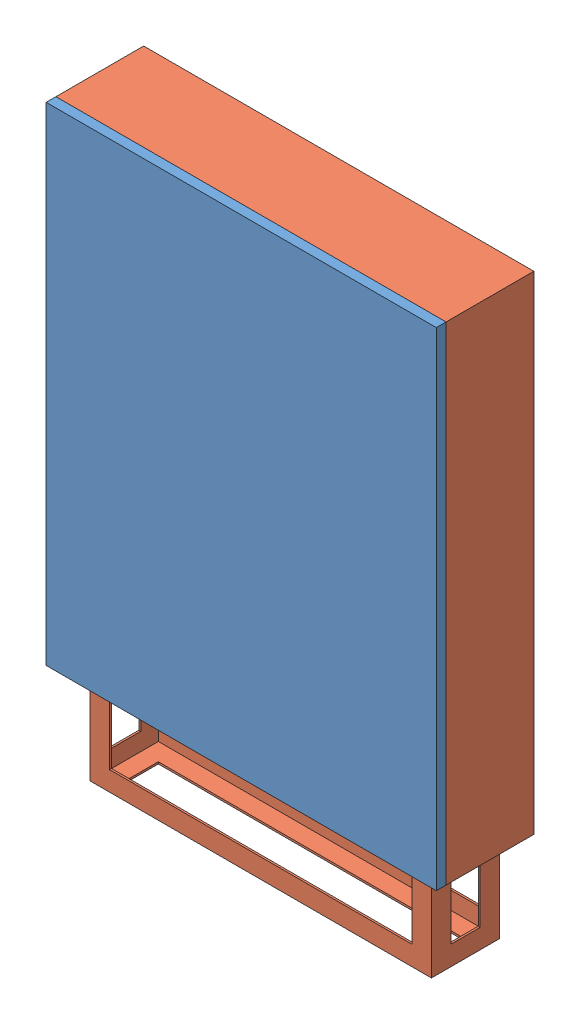
SolidWorks assembly 控制柜, configuration 打开柜门. Lengths in mm.
Overall size (800 1200 200).
2 component instances, 2 part files, 3 mates.
Components (placement in the parent):
- 柜门-1: 柜门 [Default] at (213.8611 721.5056 1056.6927) size (800 1000 20)
- 柜体-1: 柜体 [Default] at (213.8611 721.5056 876.6927) size (800 1200 180)
Mates (geometry in assembly coordinates):
- 重合1: coincident: line of 柜门-1 through (213.8611 1721.5056 1056.6927) axis (0 -1 0); line of 柜体-1 through (213.8611 1721.5056 1056.6927) axis (0 -1 0)
- 重合2: coincident: plane of 柜门-1 through (193.8699 1721.5056 1056.0995) normal (0 1 0); plane of 柜体-1 through (213.8611 1721.5056 1056.6927) normal (0 1 0)
- 重合3: coincident: line of 柜门-1 through (1013.8611 721.5056 1056.6927) axis (0 1 0); line of 柜体-1 through (1013.8611 721.5056 1056.6927) axis (0 1 0)
